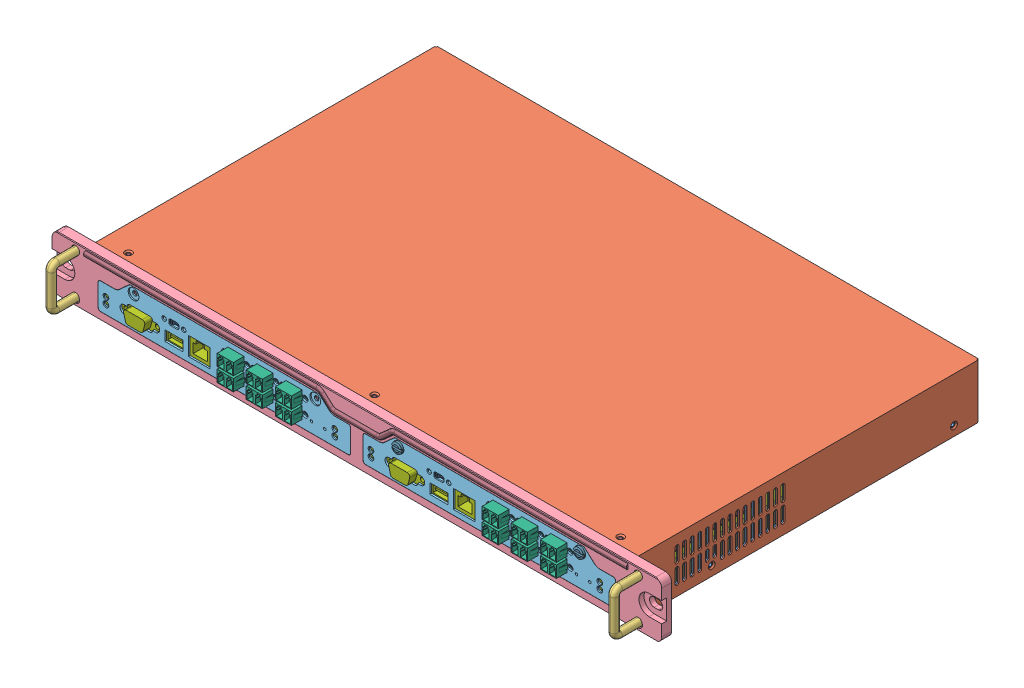
SolidWorks assembly fod-assy_asm, configuration Standard. Lengths in mm.
Overall size (483 43.5 300.15).
46 component instances, 17 part files, 0 mates.
Components (placement in the parent):
- FOD-BASE-1: FOD-BASE [Standard] at origin size (428 42.5 268.8)
- FOD-TOP-COVER-1: FOD-TOP-COVER [Standard] at (0 43.5 -17) size (430.4 43 270)
- PRT0002-1: PRT0002 [Standard] at (223 22 5) x (1 0 0) z (0 -1 0) size (6 25.15 37.6)
- PRT0002-2: PRT0002 [Standard] at (-223 22 5) x (-1 0 0) z (0 1 0) size (6 25.15 37.6)
- FOD-FRONT-PANEL-1: FOD-FRONT-PANEL [Standard] at (0 22 0) size (483 43.5 17)
- FOD-MODULE-ASSY_ASM-1: FOD-MODULE-ASSY_ASM [Standard] at (-205 9 5) size (200 30 265.8)
  - FOD-IO-PANEL-1: FOD-IO-PANEL [Standard] at (0 -2.9 1) size (200 30 14)
  - CONN-LC-TYPE-SCREW-1: CONN-LC-TYPE-SCREW [Standard] at (109 12 11.3) x (-1 0 0) z (0 0 1) size (22 9.3 25.8)
  - CONN-LC-TYPE-SCREW-2: CONN-LC-TYPE-SCREW [Standard] at (132 12 11.3) x (-1 0 0) z (0 0 1) size (22 9.3 25.8)
  - CONN-LC-TYPE-SCREW-3: CONN-LC-TYPE-SCREW [Standard] at (155 12 11.3) x (-1 0 0) z (0 0 1) size (22 9.3 25.8)
  - CONN-LC-TYPE-SCREW-4: CONN-LC-TYPE-SCREW [Standard] at (109 23 11.3) x (-1 0 0) z (0 0 1) size (22 9.3 25.8)
  - CONN-LC-TYPE-SCREW-5: CONN-LC-TYPE-SCREW [Standard] at (132 23 11.3) x (-1 0 0) z (0 0 1) size (22 9.3 25.8)
  - CONN-LC-TYPE-SCREW-6: CONN-LC-TYPE-SCREW [Standard] at (155 23 11.3) x (-1 0 0) z (0 0 1) size (22 9.3 25.8)
  - FOD-MAIN-BD-1: FOD-MAIN-BD [Standard] at origin size (200 15.1 262)
    - FOD-MAIN-BD_3-1: FOD-MAIN-BD_3 [Standard] at origin size (200 15.1 262)
    - FOD-MAIN-BD_2-1: FOD-MAIN-BD_2 [Standard] at origin size (9.8 5.5 18.1)
    - FOD-MAIN-BD-1: FOD-MAIN-BD [Standard] at origin size (9.8 5.5 18.1)
  - SLIDE-SWITCH-1: SLIDE-SWITCH [Standard] at (60 14.5 -5) size (19 6 10.5)
  - FOD-BD-COVER-1: FOD-BD-COVER [Standard] at (100 7.6 -120) size (190 9 90)
- FOD-MODULE-ASSY_ASM-2: FOD-MODULE-ASSY_ASM [Standard] at (5 9 5) size (200 30 265.8)
  - FOD-IO-PANEL-1: FOD-IO-PANEL [Standard] at (0 -2.9 1) size (200 30 14)
  - CONN-LC-TYPE-SCREW-1: CONN-LC-TYPE-SCREW [Standard] at (109 12 11.3) x (-1 0 0) z (0 0 1) size (22 9.3 25.8)
  - CONN-LC-TYPE-SCREW-2: CONN-LC-TYPE-SCREW [Standard] at (132 12 11.3) x (-1 0 0) z (0 0 1) size (22 9.3 25.8)
  - CONN-LC-TYPE-SCREW-3: CONN-LC-TYPE-SCREW [Standard] at (155 12 11.3) x (-1 0 0) z (0 0 1) size (22 9.3 25.8)
  - CONN-LC-TYPE-SCREW-4: CONN-LC-TYPE-SCREW [Standard] at (109 23 11.3) x (-1 0 0) z (0 0 1) size (22 9.3 25.8)
  - CONN-LC-TYPE-SCREW-5: CONN-LC-TYPE-SCREW [Standard] at (132 23 11.3) x (-1 0 0) z (0 0 1) size (22 9.3 25.8)
  - CONN-LC-TYPE-SCREW-6: CONN-LC-TYPE-SCREW [Standard] at (155 23 11.3) x (-1 0 0) z (0 0 1) size (22 9.3 25.8)
  - FOD-MAIN-BD-1: FOD-MAIN-BD [Standard] at origin size (200 15.1 262)
    - FOD-MAIN-BD_3-1: FOD-MAIN-BD_3 [Standard] at origin size (200 15.1 262)
    - FOD-MAIN-BD_2-1: FOD-MAIN-BD_2 [Standard] at origin size (9.8 5.5 18.1)
    - FOD-MAIN-BD-1: FOD-MAIN-BD [Standard] at origin size (9.8 5.5 18.1)
  - SLIDE-SWITCH-1: SLIDE-SWITCH [Standard] at (60 14.5 -5) size (19 6 10.5)
  - FOD-BD-COVER-1: FOD-BD-COVER [Standard] at (100 7.6 -120) size (190 9 90)
- FOD-PCB-GUIDE-1: FOD-PCB-GUIDE [Standard] at (-202.7 1 -5) size (7 14 235)
- FOD-PCB-GUIDE-2: FOD-PCB-GUIDE [Standard] at (7.3 1 -5) size (7 14 235)
- FOD-PCB-GUIDE-3: FOD-PCB-GUIDE [Standard] at (-7.3 1 -250) x (-1 0 0) z (0 0 -1) size (7 14 235)
- FOD-PCB-GUIDE-4: FOD-PCB-GUIDE [Standard] at (202.7 1 -250) x (-1 0 0) z (0 0 -1) size (7 14 235)
- FOD-DESIGN-BAR-1: FOD-DESIGN-BAR [Standard] at (0 41.9 6) size (430 13.1 3.5)
- FOD-CAP-SCREW-1: FOD-CAP-SCREW [Standard] at (177 31.1 7) size (8 8 15)
- FOD-CAP-SCREW-2: FOD-CAP-SCREW [Standard] at (33 31.1 7) size (8 8 15)
- FOD-FRONT-BRKT-1: FOD-FRONT-BRKT [Standard] at (0 38.7 0) size (370 13 11)
- FOD-SIDE-BRKT-1: FOD-SIDE-BRKT [Standard] at (213 37 0) x (-1 0 0) z (0 0 1) size (7.8 31 12)
- FOD-SIDE-BRKT-2: FOD-SIDE-BRKT [Standard] at (-213 6 0) size (7.8 31 12)
- FOD-BP-BD-ST-1: FOD-BP-BD-ST [Standard] at (-5 9 -254.8) x (1 0 0) z (0 -1 0) size (270 24.5 30)
- SLIDE-SWITCH-1: SLIDE-SWITCH [Standard] at (177 25 -261.8) x (1 0 0) z (0 0 -1) size (19 6 10.5)
- SLIDE-SWITCH-2: SLIDE-SWITCH [Standard] at (-177 19 -261.8) x (-1 0 0) z (0 0 -1) size (19 6 10.5)
